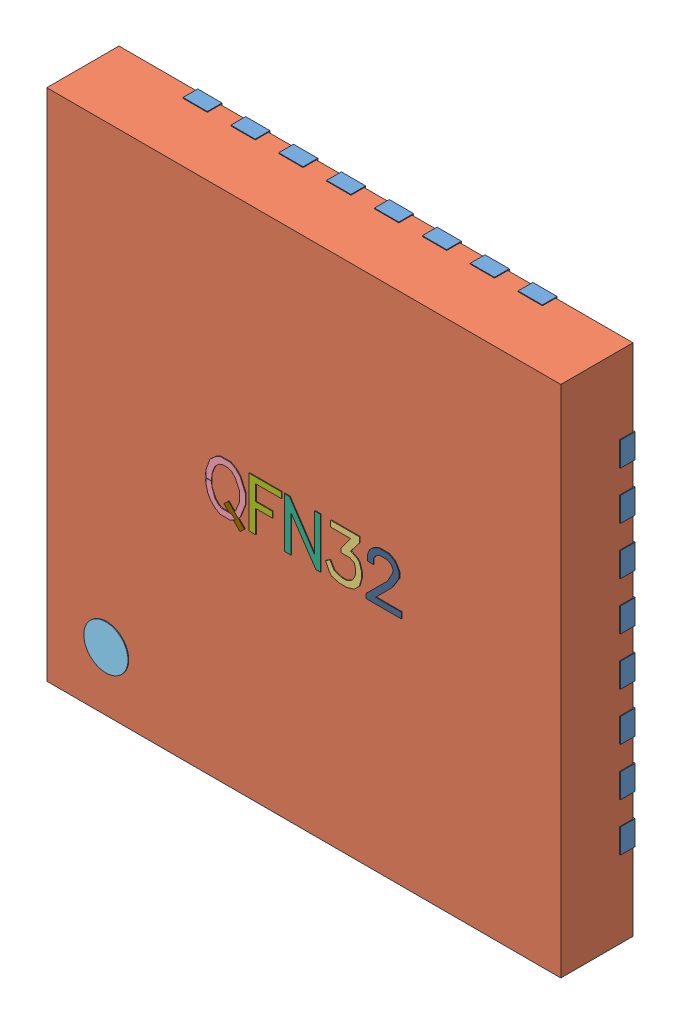
SolidWorks assembly SW3dPS-QFN-32, configuration Default. Lengths in mm.
Overall size (7 7 1.17).
84 component instances, 11 part files, 0 mates.
Components (placement in the parent):
- SW3dPS-QFN-32_Free-Models1-1: SW3dPS-QFN-32_Free-Models1 [Default] at origin size (7 7 1.06)
  - SW3dPS-QFN-32_442949713-1: SW3dPS-QFN-32_442949713 [Default] at (-0.925 2.955 0.0127) x (0 -1 0) z (0 0 1) size (0.33 0.6 0.2)
    - SW3dPS-QFN-32_Extruded9-1: SW3dPS-QFN-32_Extruded9 [Default] at origin size (0.33 0.6 0.2)
  - SW3dPS-QFN-32_442949713-2: SW3dPS-QFN-32_442949713 [Default] at (5.475 2.305 0.0127) x (0 1 0) z (0 0 1) size (0.33 0.6 0.2)
    - SW3dPS-QFN-32_Extruded9-1: SW3dPS-QFN-32_Extruded9 [Default] at origin size (0.33 0.6 0.2)
  - SW3dPS-QFN-32_442949713-3: SW3dPS-QFN-32_442949713 [Default] at (5.475 4.905 0.0127) x (0 1 0) z (0 0 1) size (0.33 0.6 0.2)
    - SW3dPS-QFN-32_Extruded9-1: SW3dPS-QFN-32_Extruded9 [Default] at origin size (0.33 0.6 0.2)
  - SW3dPS-QFN-32_442949713-4: SW3dPS-QFN-32_442949713 [Default] at (4.55 0.08 0.0127) size (0.33 0.6 0.2)
    - SW3dPS-QFN-32_Extruded9-1: SW3dPS-QFN-32_Extruded9 [Default] at origin size (0.33 0.6 0.2)
  - SW3dPS-QFN-32_442949073-1: SW3dPS-QFN-32_442949073 [Default] at (2.275 3.28 0.0327) size (6.98 6.98 0.98)
    - SW3dPS-QFN-32_Extruded10-1: SW3dPS-QFN-32_Extruded10 [Default] at origin size (6.98 6.98 0.98)
  - SW3dPS-QFN-32_442949713-5: SW3dPS-QFN-32_442949713 [Default] at (3.25 6.48 0.0127) x (-1 0 0) z (0 0 1) size (0.33 0.6 0.2)
    - SW3dPS-QFN-32_Extruded9-1: SW3dPS-QFN-32_Extruded9 [Default] at origin size (0.33 0.6 0.2)
  - SW3dPS-QFN-32_442949713-6: SW3dPS-QFN-32_442949713 [Default] at (5.475 1.005 0.0127) x (0 1 0) z (0 0 1) size (0.33 0.6 0.2)
    - SW3dPS-QFN-32_Extruded9-1: SW3dPS-QFN-32_Extruded9 [Default] at origin size (0.33 0.6 0.2)
  - SW3dPS-QFN-32_442949713-7: SW3dPS-QFN-32_442949713 [Default] at (5.475 3.605 0.0127) x (0 1 0) z (0 0 1) size (0.33 0.6 0.2)
    - SW3dPS-QFN-32_Extruded9-1: SW3dPS-QFN-32_Extruded9 [Default] at origin size (0.33 0.6 0.2)
  - SW3dPS-QFN-32_442949713-8: SW3dPS-QFN-32_442949713 [Default] at (5.475 5.555 0.0127) x (0 1 0) z (0 0 1) size (0.33 0.6 0.2)
    - SW3dPS-QFN-32_Extruded9-1: SW3dPS-QFN-32_Extruded9 [Default] at origin size (0.33 0.6 0.2)
  - SW3dPS-QFN-32_442949713-9: SW3dPS-QFN-32_442949713 [Default] at (0.65 0.08 0.0127) size (0.33 0.6 0.2)
    - SW3dPS-QFN-32_Extruded9-1: SW3dPS-QFN-32_Extruded9 [Default] at origin size (0.33 0.6 0.2)
  - SW3dPS-QFN-32_442949713-10: SW3dPS-QFN-32_442949713 [Default] at (-0.925 4.905 0.0127) x (0 -1 0) z (0 0 1) size (0.33 0.6 0.2)
    - SW3dPS-QFN-32_Extruded9-1: SW3dPS-QFN-32_Extruded9 [Default] at origin size (0.33 0.6 0.2)
  - SW3dPS-QFN-32_442941137-1: SW3dPS-QFN-32_442941137 [Default] at (2.825 3.28 1.0127) size (0.49 0.68 0.01)
    - SW3dPS-QFN-32_Extruded15-1: SW3dPS-QFN-32_Extruded15 [Default] at origin size (0.49 0.68 0.01)
  - SW3dPS-QFN-32_442947537-1: SW3dPS-QFN-32_442947537 [Default] at (1.22 3.28 1.0127) size (0.6 0.68 0.11)
    - SW3dPS-QFN-32_Extruded12-1: SW3dPS-QFN-32_Extruded12 [Default] at origin size (0.6 0.68 0.11)
  - SW3dPS-QFN-32_442949713-11: SW3dPS-QFN-32_442949713 [Default] at (1.95 0.08 0.0127) size (0.33 0.6 0.2)
    - SW3dPS-QFN-32_Extruded9-1: SW3dPS-QFN-32_Extruded9 [Default] at origin size (0.33 0.6 0.2)
  - SW3dPS-QFN-32_442949713-12: SW3dPS-QFN-32_442949713 [Default] at (-0.925 2.305 0.0127) x (0 -1 0) z (0 0 1) size (0.33 0.6 0.2)
    - SW3dPS-QFN-32_Extruded9-1: SW3dPS-QFN-32_Extruded9 [Default] at origin size (0.33 0.6 0.2)
  - SW3dPS-QFN-32_442711073-1: SW3dPS-QFN-32_442711073 [Default] at (-0.4024 0.5994 1.0127) size (0.6 0.6 0.01)
    - SW3dPS-QFN-32_Cylinder1-1: SW3dPS-QFN-32_Cylinder1 [Default] at origin size (0.6 0.6 0.01)
  - SW3dPS-QFN-32_442949713-13: SW3dPS-QFN-32_442949713 [Default] at (0.65 6.48 0.0127) x (-1 0 0) z (0 0 1) size (0.33 0.6 0.2)
    - SW3dPS-QFN-32_Extruded9-1: SW3dPS-QFN-32_Extruded9 [Default] at origin size (0.33 0.6 0.2)
  - SW3dPS-QFN-32_442949713-14: SW3dPS-QFN-32_442949713 [Default] at (2.6 6.48 0.0127) x (-1 0 0) z (0 0 1) size (0.33 0.6 0.2)
    - SW3dPS-QFN-32_Extruded9-1: SW3dPS-QFN-32_Extruded9 [Default] at origin size (0.33 0.6 0.2)
  - SW3dPS-QFN-32_442949713-15: SW3dPS-QFN-32_442949713 [Default] at (0 0.08 0.0127) size (0.33 0.6 0.2)
    - SW3dPS-QFN-32_Extruded9-1: SW3dPS-QFN-32_Extruded9 [Default] at origin size (0.33 0.6 0.2)
  - SW3dPS-QFN-32_442949713-16: SW3dPS-QFN-32_442949713 [Default] at (-0.925 3.605 0.0127) x (0 -1 0) z (0 0 1) size (0.33 0.6 0.2)
    - SW3dPS-QFN-32_Extruded9-1: SW3dPS-QFN-32_Extruded9 [Default] at origin size (0.33 0.6 0.2)
  - SW3dPS-QFN-32_442949713-17: SW3dPS-QFN-32_442949713 [Default] at (5.475 1.655 0.0127) x (0 1 0) z (0 0 1) size (0.33 0.6 0.2)
    - SW3dPS-QFN-32_Extruded9-1: SW3dPS-QFN-32_Extruded9 [Default] at origin size (0.33 0.6 0.2)
  - SW3dPS-QFN-32_442945489-1: SW3dPS-QFN-32_442945489 [Default] at (2.265 3.28 1.0127) size (0.49 0.68 0.01)
    - SW3dPS-QFN-32_Extruded17-1: SW3dPS-QFN-32_Extruded17 [Default] at origin size (0.49 0.68 0.01)
  - SW3dPS-QFN-32_442947409-1: SW3dPS-QFN-32_442947409 [Default] at (1.76 3.28 1.0127) size (0.44 0.68 0.01)
    - SW3dPS-QFN-32_Extruded11-1: SW3dPS-QFN-32_Extruded11 [Default] at origin size (0.44 0.68 0.01)
  - SW3dPS-QFN-32_442949713-18: SW3dPS-QFN-32_442949713 [Default] at (1.95 6.48 0.0127) x (-1 0 0) z (0 0 1) size (0.33 0.6 0.2)
    - SW3dPS-QFN-32_Extruded9-1: SW3dPS-QFN-32_Extruded9 [Default] at origin size (0.33 0.6 0.2)
  - SW3dPS-QFN-32_442949713-19: SW3dPS-QFN-32_442949713 [Default] at (1.3 6.48 0.0127) x (-1 0 0) z (0 0 1) size (0.33 0.6 0.2)
    - SW3dPS-QFN-32_Extruded9-1: SW3dPS-QFN-32_Extruded9 [Default] at origin size (0.33 0.6 0.2)
  - SW3dPS-QFN-32_442949713-20: SW3dPS-QFN-32_442949713 [Default] at (-0.925 5.555 0.0127) x (0 -1 0) z (0 0 1) size (0.33 0.6 0.2)
    - SW3dPS-QFN-32_Extruded9-1: SW3dPS-QFN-32_Extruded9 [Default] at origin size (0.33 0.6 0.2)
  - SW3dPS-QFN-32_442949713-21: SW3dPS-QFN-32_442949713 [Default] at (4.55 6.48 0.0127) x (-1 0 0) z (0 0 1) size (0.33 0.6 0.2)
    - SW3dPS-QFN-32_Extruded9-1: SW3dPS-QFN-32_Extruded9 [Default] at origin size (0.33 0.6 0.2)
  - SW3dPS-QFN-32_442949713-22: SW3dPS-QFN-32_442949713 [Default] at (3.25 0.08 0.0127) size (0.33 0.6 0.2)
    - SW3dPS-QFN-32_Extruded9-1: SW3dPS-QFN-32_Extruded9 [Default] at origin size (0.33 0.6 0.2)
  - SW3dPS-QFN-32_442949713-23: SW3dPS-QFN-32_442949713 [Default] at (-0.925 1.655 0.0127) x (0 -1 0) z (0 0 1) size (0.33 0.6 0.2)
    - SW3dPS-QFN-32_Extruded9-1: SW3dPS-QFN-32_Extruded9 [Default] at origin size (0.33 0.6 0.2)
  - SW3dPS-QFN-32_442949713-24: SW3dPS-QFN-32_442949713 [Default] at (5.475 4.255 0.0127) x (0 1 0) z (0 0 1) size (0.33 0.6 0.2)
    - SW3dPS-QFN-32_Extruded9-1: SW3dPS-QFN-32_Extruded9 [Default] at origin size (0.33 0.6 0.2)
  - SW3dPS-QFN-32_442951121-1: SW3dPS-QFN-32_442951121 [Default] at (2.275 3.28 0.0127) size (5.26 5.26 0.2)
    - SW3dPS-QFN-32_Extruded13-1: SW3dPS-QFN-32_Extruded13 [Default] at origin size (5.26 5.26 0.2)
  - SW3dPS-QFN-32_442945105-1: SW3dPS-QFN-32_442945105 [Default] at (1.34 3.01 1.0127) size (0.28 0.28 0.01)
    - SW3dPS-QFN-32_Extruded16-1: SW3dPS-QFN-32_Extruded16 [Default] at origin size (0.28 0.28 0.01)
  - SW3dPS-QFN-32_442949713-25: SW3dPS-QFN-32_442949713 [Default] at (-0.925 4.255 0.0127) x (0 -1 0) z (0 0 1) size (0.33 0.6 0.2)
    - SW3dPS-QFN-32_Extruded9-1: SW3dPS-QFN-32_Extruded9 [Default] at origin size (0.33 0.6 0.2)
  - SW3dPS-QFN-32_442949713-26: SW3dPS-QFN-32_442949713 [Default] at (2.6 0.08 0.0127) size (0.33 0.6 0.2)
    - SW3dPS-QFN-32_Extruded9-1: SW3dPS-QFN-32_Extruded9 [Default] at origin size (0.33 0.6 0.2)
  - SW3dPS-QFN-32_442949713-27: SW3dPS-QFN-32_442949713 [Default] at (1.3 0.08 0.0127) size (0.33 0.6 0.2)
    - SW3dPS-QFN-32_Extruded9-1: SW3dPS-QFN-32_Extruded9 [Default] at origin size (0.33 0.6 0.2)
  - SW3dPS-QFN-32_442949713-28: SW3dPS-QFN-32_442949713 [Default] at (5.475 2.955 0.0127) x (0 1 0) z (0 0 1) size (0.33 0.6 0.2)
    - SW3dPS-QFN-32_Extruded9-1: SW3dPS-QFN-32_Extruded9 [Default] at origin size (0.33 0.6 0.2)
  - SW3dPS-QFN-32_442949713-29: SW3dPS-QFN-32_442949713 [Default] at (3.9 6.48 0.0127) x (-1 0 0) z (0 0 1) size (0.33 0.6 0.2)
    - SW3dPS-QFN-32_Extruded9-1: SW3dPS-QFN-32_Extruded9 [Default] at origin size (0.33 0.6 0.2)
  - SW3dPS-QFN-32_442949713-30: SW3dPS-QFN-32_442949713 [Default] at (0 6.48 0.0127) x (-1 0 0) z (0 0 1) size (0.33 0.6 0.2)
    - SW3dPS-QFN-32_Extruded9-1: SW3dPS-QFN-32_Extruded9 [Default] at origin size (0.33 0.6 0.2)
  - SW3dPS-QFN-32_442952273-1: SW3dPS-QFN-32_442952273 [Default] at (3.37 3.28 1.0127) size (0.48 0.68 0.01)
    - SW3dPS-QFN-32_Extruded14-1: SW3dPS-QFN-32_Extruded14 [Default] at origin size (0.48 0.68 0.01)
  - SW3dPS-QFN-32_442949713-31: SW3dPS-QFN-32_442949713 [Default] at (-0.925 1.005 0.0127) x (0 -1 0) z (0 0 1) size (0.33 0.6 0.2)
    - SW3dPS-QFN-32_Extruded9-1: SW3dPS-QFN-32_Extruded9 [Default] at origin size (0.33 0.6 0.2)
  - SW3dPS-QFN-32_442949713-32: SW3dPS-QFN-32_442949713 [Default] at (3.9 0.08 0.0127) size (0.33 0.6 0.2)
    - SW3dPS-QFN-32_Extruded9-1: SW3dPS-QFN-32_Extruded9 [Default] at origin size (0.33 0.6 0.2)
- SW3dPS-QFN-32_Board1-1: SW3dPS-QFN-32_Board1 [Default] at (0 0 -0.0938) size (0.01 0.01 0.11)
